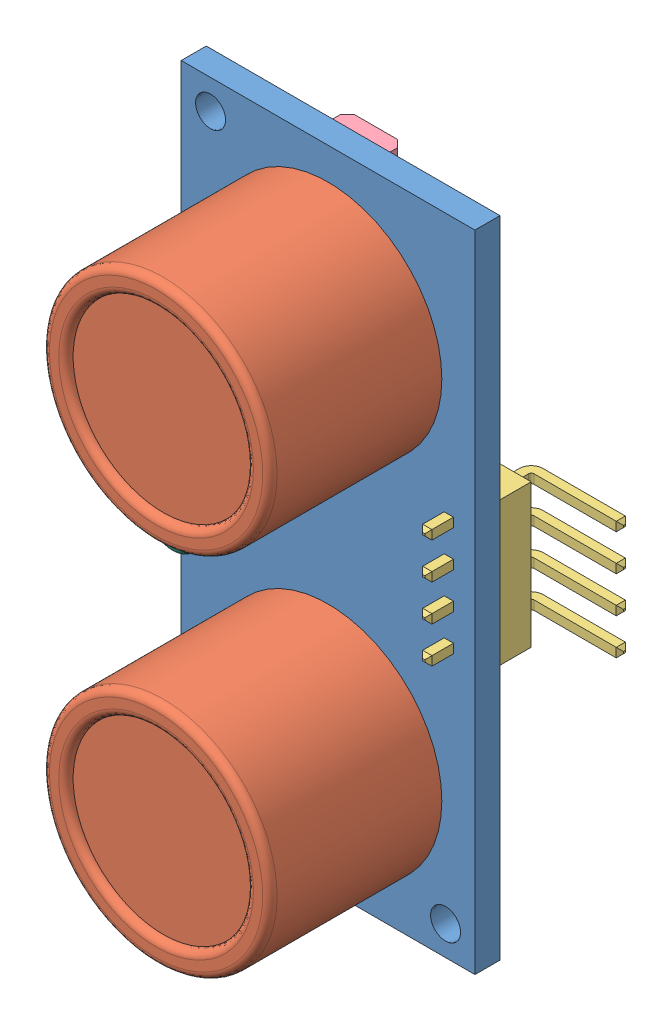
SolidWorks assembly HC-SR04 Ping Sensor, configuration Default. Lengths in mm.
Overall size (25.18 45 18.07).
14 component instances, 6 part files, 46 mates.
Components (placement in the parent):
- PCB-1: PCB [Default] at origin size (20.5 45 1.75)
- Transducer-1: Transducer [Default] at (0 -13.16 13.25) x (1 0 0) z (0 -1 0) size (15.88 12 15.88)
- Transducer-2: Transducer [Default] at (0 12.34 13.25) x (1 0 0) z (0 -1 0) size (15.88 12 15.88)
- 3 Pin Header 90 Degree-1: 3 Pin Header 90 Degree [Default] at (8.4275 0 -1.25) x (-1 0 0) z (0 -1 0) size (8 7.82 10)
- 14 Pin SMT-1: 14 Pin SMT [Default] at (-0.35 -18.5 -0.85) x (0 -1 0) z (1 0 0) size (6 1.6 8.8)
- 14 Pin SMT-2: 14 Pin SMT [Default] at (0 -0.3826 -0.85) x (1 0 0) z (0 1 0) size (6 1.6 8.8)
- 14 Pin SMT-3: 14 Pin SMT [Default] at (0 17.5274 -0.85) x (1 0 0) z (0 1 0) size (6 1.6 8.8)
- Cap1 SMT-1: Cap1 SMT [Default] at (-1.755 7.4774 -0.9689) x (0 1 0) z (-1 0 0) size (4.5 1.84 1.75)
- Cap1 SMT-2: Cap1 SMT [Default] at (6.835 7.4774 -0.9689) x (0 1 0) z (-1 0 0) size (4.5 1.84 1.75)
- Cap1 SMT-3: Cap1 SMT [Default] at (-6.835 7.4774 -0.9689) x (0 1 0) z (-1 0 0) size (4.5 1.84 1.75)
- Cap1 SMT-4: Cap1 SMT [Default] at (4.295 7.4774 -0.9689) x (0 1 0) z (-1 0 0) size (4.5 1.84 1.75)
- Cap1 SMT-5: Cap1 SMT [Default] at (1.755 7.4774 -0.9689) x (0 1 0) z (-1 0 0) size (4.5 1.84 1.75)
- Cap1 SMT-6: Cap1 SMT [Default] at (-4.295 7.4774 -0.9689) x (0 1 0) z (-1 0 0) size (4.5 1.84 1.75)
- HC-SR04 Crystal-1: HC-SR04 Crystal [Default] at (-8.3 0 1.75) x (0 -1 0) z (0 0 1) size (10 3.5 2.7)
Mates (geometry in assembly coordinates):
- Coincident1: coincident: plane of PCB-1 through (-10.25 -22.5 1.75) normal (0 0 1); plane of Transducer-2 through (0 12.34 1.75) normal (0 0 -1)
- Coincident2: coincident: plane of PCB-1 through (-10.25 -22.5 1.75) normal (0 0 1); plane of Transducer-1 through (0 -13.16 1.75) normal (0 0 -1)
- Coincident3: coincident: plane of PCB-1 through (0 0 0) normal (1 0 0); plane of Transducer-1
- Coincident4: coincident: plane of PCB-1 through (0 0 0) normal (1 0 0); plane of Transducer-2
- Distance2: distance = 9.34 mm: plane of PCB-1 through (-10.25 -22.5 1.75) normal (0 -1 0); point of Transducer-1
- Distance3: distance = 10.16 mm: plane of PCB-1 through (-10.25 22.5 1.75) normal (0 1 0); point of Transducer-2
- Coincident8: coincident: plane of PCB-1 through (0 0 0) normal (0 1 0); plane of 3 Pin Header 90 Degree-1 through (8.4275 0 -1.25) normal (0 -1 0)
- Coincident9: coincident: plane of PCB-1 through (-10.25 -22.5 0) normal (0 0 -1); plane of 14 Pin SMT-1 through (-0.6 -21.5 0) normal (0 0 1)
- Coincident10: coincident: plane of PCB-1 through (-10.25 -22.5 0) normal (0 0 -1); plane of 14 Pin SMT-2 through (3 -0.6326 0) normal (0 0 1)
- Coincident11: coincident: plane of PCB-1 through (-10.25 -22.5 0) normal (0 0 -1); plane of 14 Pin SMT-3 through (3 18.5274 0) normal (0 0 1)
- Coincident13: coincident: plane of PCB-1 through (0 0 0) normal (1 0 0); plane of 14 Pin SMT-2
- Coincident14: coincident: plane of PCB-1 through (0 0 0) normal (1 0 0); plane of 14 Pin SMT-3
- Distance6: distance = 9.11 mm: plane of 14 Pin SMT-2 through (-2 4.0174 -1.6) normal (0 1 0); plane of 14 Pin SMT-3 through (-2 13.1274 -1.6) normal (0 -1 0)
- Coincident15: coincident: plane of PCB-1 through (-10.25 -22.5 0) normal (0 0 -1); plane of Cap1 SMT-1 through (-2.005 9.7274 0) normal (0 0 1)
- Coincident16: coincident: plane of PCB-1 through (-10.25 -22.5 0) normal (0 0 -1); plane of Cap1 SMT-2 through (6.585 9.7274 0) normal (0 0 1)
- Coincident17: coincident: plane of PCB-1 through (-10.25 -22.5 0) normal (0 0 -1); plane of Cap1 SMT-3 through (-7.085 9.7274 0) normal (0 0 1)
- Coincident18: coincident: plane of PCB-1 through (-10.25 -22.5 0) normal (0 0 -1); plane of Cap1 SMT-4 through (4.045 9.7274 0) normal (0 0 1)
- Coincident19: coincident: plane of PCB-1 through (-10.25 -22.5 0) normal (0 0 -1); plane of Cap1 SMT-5 through (1.505 9.7274 0) normal (0 0 1)
- Coincident20: coincident: plane of PCB-1 through (-10.25 -22.5 0) normal (0 0 -1); plane of Cap1 SMT-6 through (-4.545 9.7274 0) normal (0 0 1)
- Parallel1: parallel: plane of Cap1 SMT-4 through (3.42 5.7274 -1.8439) normal (0 -1 0); plane of Cap1 SMT-5 through (0.88 5.7274 -1.8439) normal (0 -1 0)
- Parallel2: parallel: plane of Cap1 SMT-2 through (5.96 5.7274 -1.8439) normal (0 -1 0); plane of Cap1 SMT-4 through (3.42 5.7274 -1.8439) normal (0 -1 0)
- Parallel3: parallel: plane of PCB-1 through (-10.25 -22.5 1.75) normal (0 -1 0); plane of Cap1 SMT-2 through (5.96 5.7274 -1.8439) normal (0 -1 0)
- Distance7: distance = 0.79 mm: plane of Cap1 SMT-2 through (5.96 5.7274 -1.8439) normal (-1 0 0); plane of Cap1 SMT-4 through (5.17 5.7274 -1.8439) normal (1 0 0)
- Distance8: distance = 0.79 mm: plane of Cap1 SMT-4 through (3.42 5.7274 -1.8439) normal (-1 0 0); plane of Cap1 SMT-5 through (2.63 5.7274 -1.8439) normal (1 0 0)
- Distance9: distance = 2.54 mm: plane of PCB-1 through (10.25 22.5 1.75) normal (1 0 0); plane of Cap1 SMT-2 through (7.71 5.7274 -1.8439) normal (1 0 0)
- Coincident21: coincident: plane of Cap1 SMT-4 through (3.42 9.2274 -0.0939) normal (0 1 0); plane of Cap1 SMT-5 through (0.88 9.2274 -0.0939) normal (0 1 0)
- Coincident22: coincident: plane of Cap1 SMT-2 through (5.96 9.2274 -0.0939) normal (0 1 0); plane of Cap1 SMT-4 through (3.42 9.2274 -0.0939) normal (0 1 0)
- Parallel4: parallel: plane of Cap1 SMT-3 through (-7.71 5.7274 -1.8439) normal (0 -1 0); plane of Cap1 SMT-6 through (-5.17 5.7274 -1.8439) normal (0 -1 0)
- Parallel5: parallel: plane of Cap1 SMT-1 through (-2.63 5.7274 -1.8439) normal (0 -1 0); plane of Cap1 SMT-6 through (-5.17 5.7274 -1.8439) normal (0 -1 0)
- Distance11: distance = 0.79 mm: plane of Cap1 SMT-1 through (-2.63 5.7274 -1.8439) normal (-1 0 0); plane of Cap1 SMT-6 through (-3.42 5.7274 -1.8439) normal (1 0 0)
- Distance12: distance = 0.79 mm: plane of Cap1 SMT-3 through (-5.96 5.7274 -1.8439) normal (1 0 0); plane of Cap1 SMT-6 through (-5.17 5.7274 -1.8439) normal (-1 0 0)
- Coincident23: coincident: plane of Cap1 SMT-3 through (-7.71 9.2274 -0.0939) normal (0 1 0); plane of Cap1 SMT-6 through (-5.17 9.2274 -0.0939) normal (0 1 0)
- Coincident24: coincident: plane of Cap1 SMT-1 through (-2.63 9.2274 -0.0939) normal (0 1 0); plane of Cap1 SMT-6 through (-5.17 9.2274 -0.0939) normal (0 1 0)
- Parallel6: parallel: plane of PCB-1 through (-10.25 -22.5 1.75) normal (0 -1 0); plane of Cap1 SMT-3 through (-7.71 5.7274 -1.8439) normal (0 -1 0)
- Distance13: distance = 2.54 mm: plane of PCB-1 through (-10.25 22.5 1.75) normal (-1 0 0); plane of Cap1 SMT-3 through (-7.71 5.7274 -1.8439) normal (-1 0 0)
- Coincident25: coincident: plane of Cap1 SMT-1 through (-2.63 9.2274 -0.0939) normal (0 1 0); plane of Cap1 SMT-5 through (0.88 9.2274 -0.0939) normal (0 1 0)
- Distance15: distance = 1.71 mm: plane of 14 Pin SMT-2 through (-2 4.0174 -1.6) normal (0 1 0); plane of Cap1 SMT-5 through (0.88 5.7274 -1.8439) normal (0 -1 0)
- Coincident26: coincident: plane of PCB-1 through (-10.25 -22.5 0) normal (0 0 -1); plane of 3 Pin Header 90 Degree-1 through (9.9275 -5 0) normal (0 0 1)
- Distance16: distance = 1.5 mm: plane of 3 Pin Header 90 Degree-1 through (8.75 4.4 -2.5) normal (1 0 0); plane of PCB-1 through (10.25 22.5 1.75) normal (1 0 0)
- Parallel7: parallel: plane of PCB-1 through (-10.25 22.5 1.75) normal (-1 0 0); plane of 14 Pin SMT-1 through (4.05 -16.5 -1.6) normal (1 0 0)
- Distance17: distance = 5.5 mm: plane of 14 Pin SMT-1 through (-4.75 -16.5 -1.6) normal (-1 0 0); plane of PCB-1 through (-10.25 22.5 1.75) normal (-1 0 0)
- Distance18: distance = 2 mm: plane of 14 Pin SMT-1 through (4.05 -20.5 -0.1) normal (0 -1 0); plane of PCB-1 through (-10.25 -22.5 1.75) normal (0 -1 0)
- Distance19: distance = 0.5726 mm: plane of 14 Pin SMT-3 through (-2 21.9274 -1.6) normal (0 1 0); plane of PCB-1 through (-10.25 22.5 1.75) normal (0 1 0)
- Distance20: distance = 0.2 mm: plane of PCB-1 through (-10.25 22.5 1.75) normal (-1 0 0); plane of HC-SR04 Crystal-1 through (-10.05 3.25 4.45) normal (-1 0 0)
- Coincident36: coincident: plane of PCB-1 through (-10.25 -22.5 1.75) normal (0 0 1); plane of HC-SR04 Crystal-1 through (-8.3 3.25 1.75) normal (0 0 -1)
- Coincident37: coincident: plane of HC-SR04 Crystal-1; plane of assembly through (0 0 0) normal (0 1 0)
